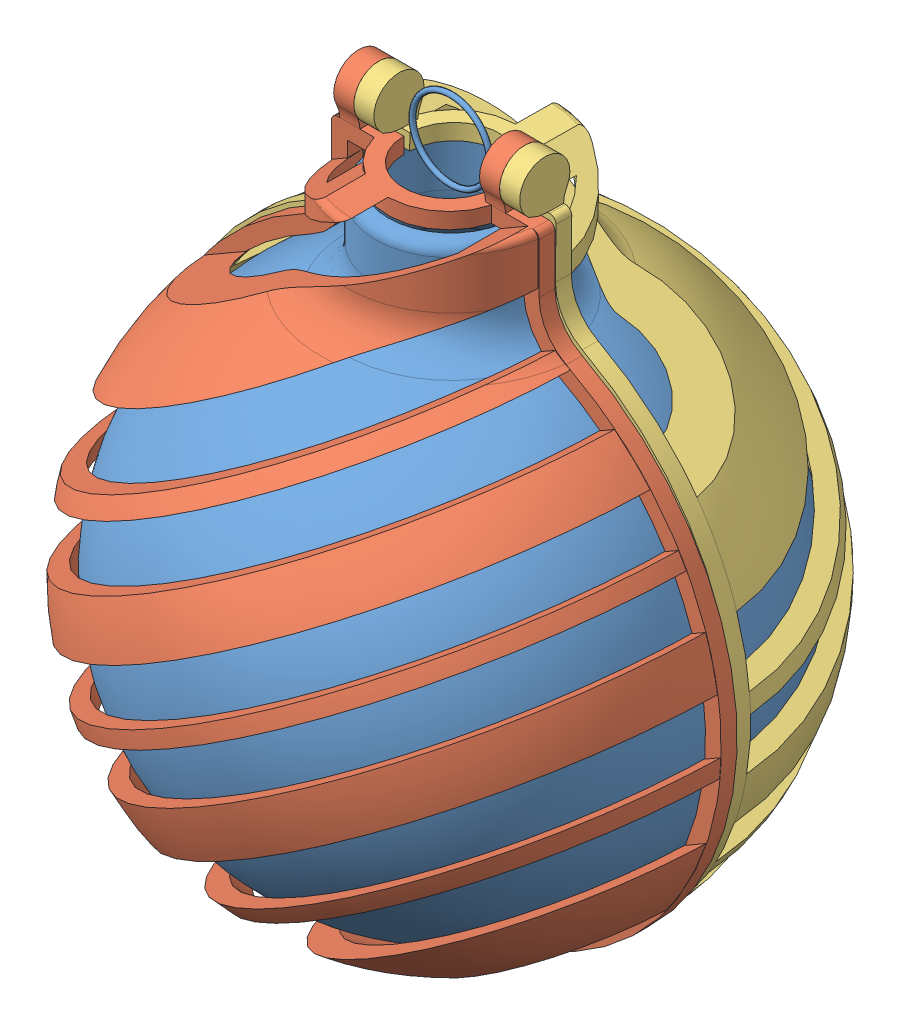
SolidWorks assembly Cage 1, configuration Default. Lengths in mm.
Overall size (72.9 89.18 73.08).
3 component instances, 3 part files, 2 mates.
Components (placement in the parent):
- Ornament^Cage 1-1: Ornament^Cage 1 [Default] at origin size (66.67 86.04 66.67) (virtual)
- Cage Half 1-1: Cage Half 1 [Default] at origin size (72.26 87.24 39.7)
- Cage Half 2-1: Cage Half 2 [Default] at (-0.635 -0.0016 -0.3401) x (-1 0 0) z (0 -0.009464 -0.999955) size (72.26 87.24 39.7)
Mates (geometry in assembly coordinates):
- Concentric1: concentric aligned: cylinder of Cage Half 1-1 through (-12.065 47.9367 -0.3969) axis (1 0 0) radius 1.905; cylinder of Cage Half 2-1 through (-12.065 47.9367 -0.3969) axis (1 0 0) radius 1.5875
- Coincident2: coincident anti-aligned: plane of Cage Half 1-1 through (-9.525 49.9425 0) normal (1 0 0); plane of Cage Half 2-1 through (-9.525 49.9387 -0.8127) normal (-1 0 0)
